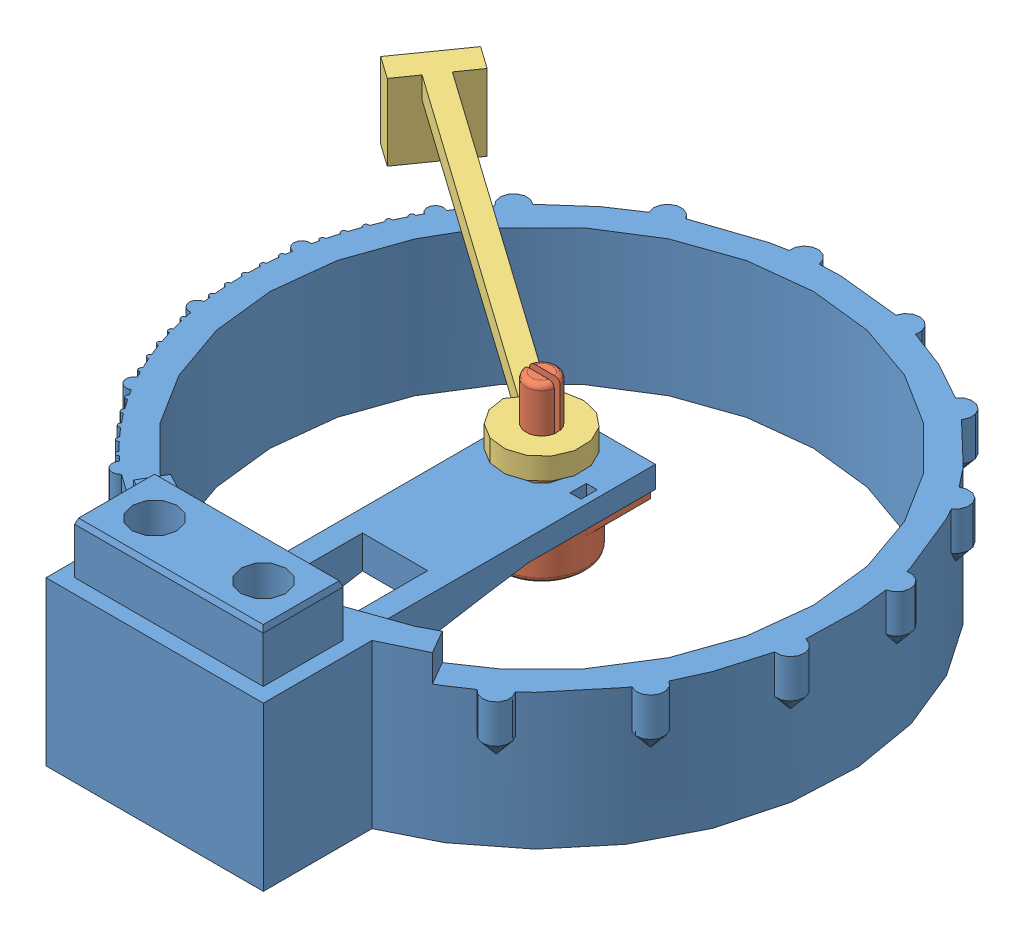
SolidWorks assembly quadrant_axis, configuration По умолчанию. Lengths in mm.
Overall size (130.6 39.5 128.37).
3 component instances, 3 part files, 5 mates.
Components (placement in the parent):
- throttle_quadrant_axis_module_throttle_quadrant01-8: throttle_quadrant_axis_module_throttle_quadrant01 [По умолчанию] at origin size (112.56 39.5 128.37)
- 16K1-B10K-1: 16K1-B10K [По умолчанию] at (0 9.1 0) x (0 0 -1) z (1 0 0) size (20 28.16 16.3)
- throttle_quadrant_axis_module_slider_throttle_quadrant02-1: throttle_quadrant_axis_module_slider_throttle_quadrant02 [По умолчанию] at (-32.6826 25 -23.0619) x (0.576547 0 -0.817064) z (0.817064 0 0.576547) size (15.6 14 92.5)
Mates (geometry in assembly coordinates):
- Concentric6: concentric anti-aligned: cylinder of throttle_quadrant_axis_module_throttle_quadrant01-8 through (0 0 0) axis (0 1 0) radius 3.7; cylinder of 16K1-B10K-1 through (0 24.4 0) axis (0 -1 0) radius 3.35
- Parallel1: parallel aligned: plane of throttle_quadrant_axis_module_throttle_quadrant01-8 through (10 22 54.0833) normal (1 0 0); plane of 16K1-B10K-1 through (8.15 16.2 0) normal (1 0 0)
- Coincident13: coincident anti-aligned: plane of throttle_quadrant_axis_module_throttle_quadrant01-8 through (0 18 0) normal (0 -1 0); plane of 16K1-B10K-1 through (0 18 0) normal (0 1 0)
- Concentric7: concentric aligned: cylinder of 16K1-B10K-1 through (0 37.2 0) axis (0 -1 0) radius 2.9; cylinder of throttle_quadrant_axis_module_slider_throttle_quadrant02-1 through (0 29 0) axis (0 -1 0) radius 3.1
- Coincident14: coincident anti-aligned: plane of throttle_quadrant_axis_module_throttle_quadrant01-8 through (0 25 0) normal (0 1 0); plane of throttle_quadrant_axis_module_slider_throttle_quadrant02-1 through (-32.6826 25 -23.0619) normal (0 -1 0)
